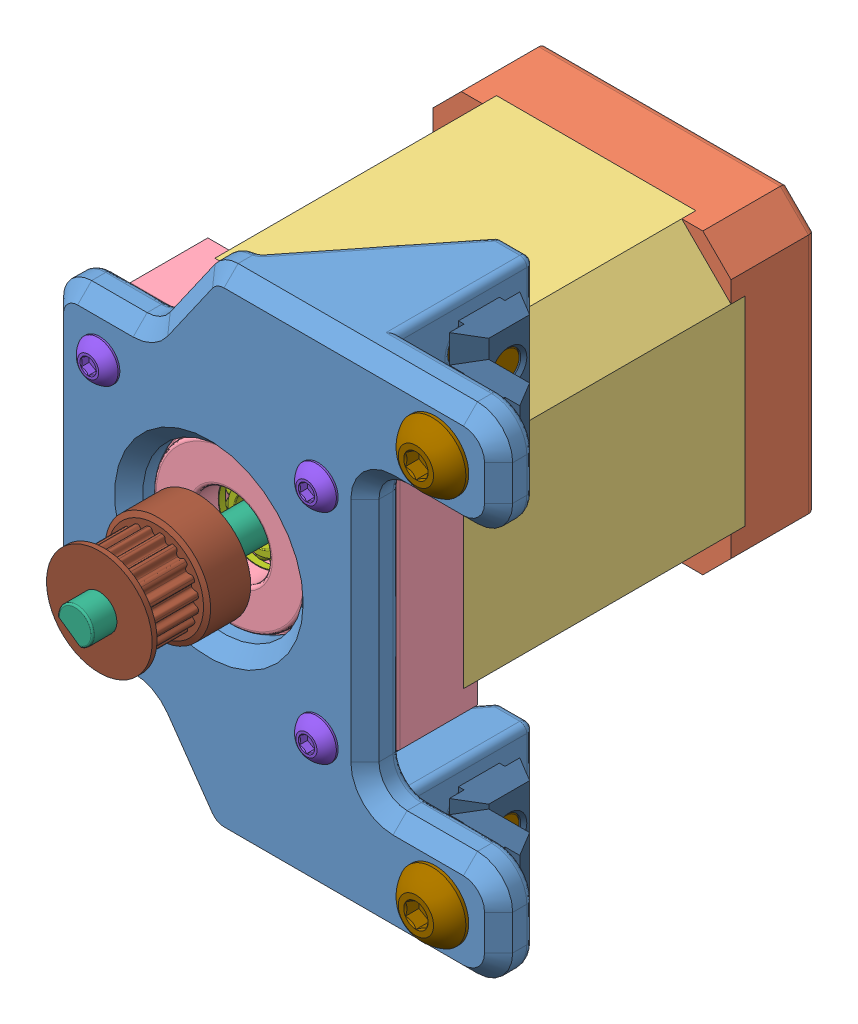
SolidWorks assembly Motor_Mount_With_Nema17_60mm, configuration Default. Lengths in mm.
Overall size (63.8 70.3 84.16).
25 component instances, 11 part files, 40 mates.
Components (placement in the parent):
- External_Motor-1: External_Motor [Default] at origin size (63.8 70.3 24)
- NEMA_17_60mm_1.5A-1: NEMA_17_60mm_1.5A [Predeterminado] at (10.3955 -4.6172 -60) size (42.3 42.3 84.16)
  - Base-1: Base [Predeterminado] at (-10.3955 4.6172 0) size (42.3 42.3 12)
  - Body_60mm-1: Body_60mm [Predeterminado] at (-10.3955 4.6172 10) size (42.3 42.3 40)
  - FaceCap-1: FaceCap [Predeterminado] at (-10.3955 4.6172 60) x (-1 0 0) z (0 0 -1) size (42.3 42.3 14)
  - 3mmX50mm_Sockethead(McMaster_91290A137)-1: 3mmX50mm_Sockethead(McMaster_91290A137) [91290A137] at (5.1045 20.1172 53) x (-0.078076 -0.996947 0) z (0 0 1) size (5.5 5.5 53.26)
  - 3mmX50mm_Sockethead(McMaster_91290A137)-2: 3mmX50mm_Sockethead(McMaster_91290A137) [91290A137] at (-25.8955 20.1172 53) x (0.373638 -0.927575 0) z (0 0 1) size (5.5 5.5 53.26)
  - 3mmX50mm_Sockethead(McMaster_91290A137)-3: 3mmX50mm_Sockethead(McMaster_91290A137) [91290A137] at (-25.8955 -10.8828 53) x (-0.535522 -0.844521 0) z (0 0 1) size (5.5 5.5 53.26)
  - 3mmX50mm_Sockethead(McMaster_91290A137)-4: 3mmX50mm_Sockethead(McMaster_91290A137) [91290A137] at (5.1045 -10.8828 53) x (-0.438078 -0.898937 0) z (0 0 1) size (5.5 5.5 53.26)
  - Shaft_60mm-1: Shaft_60mm [Predeterminado] at (-10.3955 4.6172 0) x (0.574856 0.818255 0) z (0 0 1) size (5 5 84.02)
  - instrument ball bearing_68_am-2: instrument ball bearing_68_am [PreviewCfg] at (-10.3955 4.6172 56.5875) x (0 0 -1) z (0.994238 0.107199 0) size (3.17 12.7 12.7)
  - instrument ball bearing_68_am-4: instrument ball bearing_68_am [PreviewCfg] at (-10.3955 4.6172 3.4125) x (0 0 1) z (-0.739703 -0.672934 0) size (3.17 12.7 12.7)
- 3mmX10mm_Buttonhead(McMaster_94500A223)-3: 3mmX10mm_Buttonhead(McMaster_94500A223) [94500A223] at (-15.5 -15.5 6.65) x (-1 0 0) z (0 0 1) size (5.7 5.7 11.96)
- 3mmX10mm_Buttonhead(McMaster_94500A223)-4: 3mmX10mm_Buttonhead(McMaster_94500A223) [94500A223] at (15.5 15.5 6.65) x (-1 0 0) z (0 0 1) size (5.7 5.7 11.96)
- 3mmX10mm_Buttonhead(McMaster_94500A223)-5: 3mmX10mm_Buttonhead(McMaster_94500A223) [94500A223] at (-15.5 15.5 6.65) x (-0.5 -0.866025 0) z (0 0 1) size (5.7 5.7 11.96)
- 3mmX10mm_Buttonhead(McMaster_94500A223)-6: 3mmX10mm_Buttonhead(McMaster_94500A223) [94500A223] at (15.5 -15.5 6.65) x (-0.5 0.866025 0) z (0 0 1) size (5.7 5.7 11.96)
- 5mmX10mm_Buttonhead(McMaster_91239A224)-1: 5mmX10mm_Buttonhead(McMaster_91239A224) [91239A224] at (32.15 -27.65 7.75) size (9.5 9.5 13.21)
- 5mmX10mm_Buttonhead(McMaster_91239A224)-2: 5mmX10mm_Buttonhead(McMaster_91239A224) [91239A224] at (32.15 27.65 7.75) size (9.5 9.5 13.21)
- 5mmX10mm_Buttonhead(McMaster_91239A224)-3: 5mmX10mm_Buttonhead(McMaster_91239A224) [91239A224] at (14.4 -28.65 -10) x (0 0 1) z (-1 0 0) size (9.5 9.5 13.21)
- 5mmX10mm_Buttonhead(McMaster_91239A224)-4: 5mmX10mm_Buttonhead(McMaster_91239A224) [91239A224] at (14.4 28.65 -10) x (0 0 1) z (-1 0 0) size (9.5 9.5 13.21)
- HNTTSN5-5-1: HNTTSN5-5 [Default] at (23.35 -28.65 -10) x (-1 0 0) z (0 -1 0) size (4.3 10 10)
- HNTTSN5-5-2: HNTTSN5-5 [Default] at (32.15 -27.65 -1.2) x (0 0 1) z (0 -1 0) size (4.3 10 10)
- HNTTSN5-5-3: HNTTSN5-5 [Default] at (23.35 28.65 -10) x (-1 0 0) z (0 -1 0) size (4.3 10 10)
- HNTTSN5-5-4: HNTTSN5-5 [Default] at (32.15 27.65 -1.2) x (0 0 1) z (0 -1 0) size (4.3 10 10)
- GT2_Aluminum_Timing_Pulley_20_Tooth-1: GT2_Aluminum_Timing_Pulley_20_Tooth [Default] at (0 0 6.5624) x (-0.986807 -0.161898 0) z (-0.161898 0.986807 0) size (15 14 15)
Mates (geometry in assembly coordinates):
- Coincident1: coincident anti-aligned: plane of External_Motor-1 through (36.15 30.15 0) normal (0 0 -1); plane of NEMA_17_60mm_1.5A-1/FaceCap-1 through (0 0 0) normal (0 0 1)
- Concentric1: concentric anti-aligned: circle of External_Motor-1; circle of NEMA_17_60mm_1.5A-1/FaceCap-1
- Parallel1: parallel aligned: plane of External_Motor-1 through (22.15 -16.15 5) normal (1 0 0); plane of NEMA_17_60mm_1.5A-1/FaceCap-1 through (21.15 17.15 -12) normal (1 0 0)
- Coincident10: coincident anti-aligned: plane of External_Motor-1 through (36.15 30.15 5) normal (0 0 1); plane of 5mmX10mm_Buttonhead(McMaster_91239A224)-1 through (32.15 -32.4 5) normal (0 0 -1)
- Coincident11: coincident anti-aligned: plane of External_Motor-1 through (36.15 30.15 5) normal (0 0 1); plane of 5mmX10mm_Buttonhead(McMaster_91239A224)-2 through (32.15 22.9 5) normal (0 0 -1)
- Coincident12: coincident anti-aligned: plane of External_Motor-1 through (17.15 -28.65 -10) normal (-1 0 0); plane of 5mmX10mm_Buttonhead(McMaster_91239A224)-3 through (17.15 -33.4 -10) normal (1 0 0)
- Coincident13: coincident anti-aligned: plane of External_Motor-1 through (17.15 28.65 -10) normal (-1 0 0); plane of 5mmX10mm_Buttonhead(McMaster_91239A224)-4 through (17.15 23.9 -10) normal (1 0 0)
- Concentric6: concentric anti-aligned: cylinder of External_Motor-1 through (17.15 28.65 -10) axis (1 0 0) radius 2.65; circle of 5mmX10mm_Buttonhead(McMaster_91239A224)-4
- Concentric7: concentric anti-aligned: cylinder of External_Motor-1 through (17.15 -28.65 -10) axis (1 0 0) radius 2.65; circle of 5mmX10mm_Buttonhead(McMaster_91239A224)-3
- Concentric8: concentric anti-aligned: cylinder of External_Motor-1 through (32.15 -27.65 5) axis (0 0 -1) radius 2.65; circle of 5mmX10mm_Buttonhead(McMaster_91239A224)-1
- Concentric9: concentric anti-aligned: cylinder of External_Motor-1 through (32.15 27.65 5) axis (0 0 -1) radius 2.65; circle of 5mmX10mm_Buttonhead(McMaster_91239A224)-2
- Concentric10: concentric aligned: cylinder of External_Motor-1 through (17.15 -28.65 -10) axis (1 0 0) radius 2.65; cylinder of HNTTSN5-5-1 through (23.35 -28.65 -10) axis (1 0 0) radius 2.067
- Concentric11: concentric aligned: cylinder of External_Motor-1 through (17.15 28.65 -10) axis (1 0 0) radius 2.65; cylinder of HNTTSN5-5-3 through (23.35 28.65 -10) axis (1 0 0) radius 2.067
- Concentric12: concentric aligned: cylinder of External_Motor-1 through (32.15 27.65 5) axis (0 0 -1) radius 2.65; cylinder of HNTTSN5-5-4 through (32.15 27.65 -1.2) axis (0 0 -1) radius 2.067
- Concentric13: concentric aligned: cylinder of External_Motor-1 through (32.15 -27.65 5) axis (0 0 -1) radius 2.65; cylinder of HNTTSN5-5-2 through (32.15 -27.65 -1.2) axis (0 0 -1) radius 2.067
- Parallel6: parallel aligned: plane of External_Motor-1 through (2.15 -35.15 5) normal (0 -1 0); plane of HNTTSN5-5-1 through (23.35 -33.65 -10) normal (0 -1 0)
- Parallel7: parallel aligned: plane of External_Motor-1 through (2.15 -35.15 5) normal (0 -1 0); plane of HNTTSN5-5-2 through (32.15 -32.65 -1.2) normal (0 -1 0)
- Parallel8: parallel aligned: plane of External_Motor-1 through (2.15 -35.15 5) normal (0 -1 0); plane of HNTTSN5-5-4 through (32.15 22.65 -1.2) normal (0 -1 0)
- Parallel9: parallel aligned: plane of External_Motor-1 through (2.15 -35.15 5) normal (0 -1 0); plane of HNTTSN5-5-3 through (23.35 23.65 -10) normal (0 -1 0)
- Distance1: distance = 2 mm anti-aligned: plane of External_Motor-1 through (22.15 -22.15 0) normal (1 0 0); plane of HNTTSN5-5-1 through (24.15 -33.65 -12.9) normal (-1 0 0)
- Distance2: distance = 2 mm anti-aligned: plane of External_Motor-1 through (22.15 -22.15 0) normal (1 0 0); plane of HNTTSN5-5-3 through (24.15 23.65 -12.9) normal (-1 0 0)
- Distance3: distance = 2 mm anti-aligned: plane of External_Motor-1 through (36.15 30.15 0) normal (0 0 -1); plane of HNTTSN5-5-2 through (37.15 -32.65 -2) normal (0 0 1)
- Distance4: distance = 2 mm anti-aligned: plane of External_Motor-1 through (36.15 30.15 0) normal (0 0 -1); plane of HNTTSN5-5-4 through (37.15 22.65 -2) normal (0 0 1)
- Concentric14: concentric aligned: cylinder of NEMA_17_60mm_1.5A-1/Shaft_60mm-1 through (0 0 24) axis (0 0 -1) radius 2.5; cylinder of GT2_Aluminum_Timing_Pulley_20_Tooth-1 through (0 0 20.5624) axis (0 0 -1) radius 2.5
- Coincident14: coincident aligned: plane of 3mmX10mm_Buttonhead(McMaster_94500A223)-3 through (-15.5 -12.65 5) normal (0 0 -1); plane of 3mmX10mm_Buttonhead(McMaster_94500A223)-5 through (-17.9682 16.925 5) normal (0 0 -1)
- Coincident15: coincident aligned: plane of 3mmX10mm_Buttonhead(McMaster_94500A223)-3 through (-15.5 -12.65 5) normal (0 0 -1); plane of 3mmX10mm_Buttonhead(McMaster_94500A223)-6 through (17.9682 -14.075 5) normal (0 0 -1)
- Coincident16: coincident aligned: plane of 3mmX10mm_Buttonhead(McMaster_94500A223)-3 through (-15.5 -12.65 5) normal (0 0 -1); plane of 3mmX10mm_Buttonhead(McMaster_94500A223)-4 through (15.5 18.35 5) normal (0 0 -1)
- Coincident17: coincident anti-aligned: plane of External_Motor-1 through (36.15 30.15 5) normal (0 0 1); plane of 3mmX10mm_Buttonhead(McMaster_94500A223)-3 through (-15.5 -12.65 5) normal (0 0 -1)
- Concentric15: concentric anti-aligned: cylinder of External_Motor-1 through (-15.5 -15.5 5) axis (0 0 -1) radius 1.65; cylinder of 3mmX10mm_Buttonhead(McMaster_94500A223)-3 through (-15.5 -15.5 6.65) axis (0 0 1) radius 2.85
- Concentric16: concentric anti-aligned: cylinder of External_Motor-1 through (-15.5 15.5 5) axis (0 0 -1) radius 1.65; cylinder of 3mmX10mm_Buttonhead(McMaster_94500A223)-5 through (-15.5 15.5 6.65) axis (0 0 1) radius 2.85
- Concentric17: concentric anti-aligned: cylinder of External_Motor-1 through (15.5 -15.5 5) axis (0 0 -1) radius 1.65; cylinder of 3mmX10mm_Buttonhead(McMaster_94500A223)-6 through (15.5 -15.5 6.65) axis (0 0 1) radius 2.85
- Concentric18: concentric anti-aligned: cylinder of External_Motor-1 through (15.5 15.5 5) axis (0 0 -1) radius 1.65; cylinder of 3mmX10mm_Buttonhead(McMaster_94500A223)-4 through (15.5 15.5 6.65) axis (0 0 1) radius 2.85
- Parallel10: parallel aligned: plane of External_Motor-1 through (-22.65 -18.65 5) normal (-1 0 0); plane of 3mmX10mm_Buttonhead(McMaster_94500A223)-3 through (-14.5 -16.0774 5.495) normal (-1 0 0)
- Parallel11: parallel aligned: plane of External_Motor-1 through (-22.65 -18.65 5) normal (-1 0 0); plane of 3mmX10mm_Buttonhead(McMaster_94500A223)-5 through (-14.5 14.9226 5.495) normal (-1 0 0)
- Parallel12: parallel aligned: plane of External_Motor-1 through (-22.65 -18.65 5) normal (-1 0 0); plane of 3mmX10mm_Buttonhead(McMaster_94500A223)-4 through (16.5 14.9226 5.495) normal (-1 0 0)
- Parallel13: parallel aligned: plane of External_Motor-1 through (-22.65 -18.65 5) normal (-1 0 0); plane of 3mmX10mm_Buttonhead(McMaster_94500A223)-6 through (16.5 -16.0774 5.495) normal (-1 0 0)
- Parallel14: parallel aligned: plane of 5mmX10mm_Buttonhead(McMaster_91239A224)-1 through (30.65 -26.784 5.825) normal (1 0 0); plane of External_Motor-1 through (41.15 -30.15 5) normal (1 0 0)
- Parallel15: parallel aligned: plane of 5mmX10mm_Buttonhead(McMaster_91239A224)-1 through (30.65 -26.784 5.825) normal (1 0 0); plane of 5mmX10mm_Buttonhead(McMaster_91239A224)-2 through (30.65 28.516 5.825) normal (1 0 0)
- Parallel16: parallel aligned: plane of External_Motor-1 through (22.15 -22.15 -19) normal (0 0 -1); plane of 5mmX10mm_Buttonhead(McMaster_91239A224)-3 through (16.325 -29.516 -8.5) normal (0 0 -1)
- Parallel17: parallel aligned: plane of External_Motor-1 through (22.15 -22.15 -19) normal (0 0 -1); plane of 5mmX10mm_Buttonhead(McMaster_91239A224)-4 through (16.325 27.784 -8.5) normal (0 0 -1)
